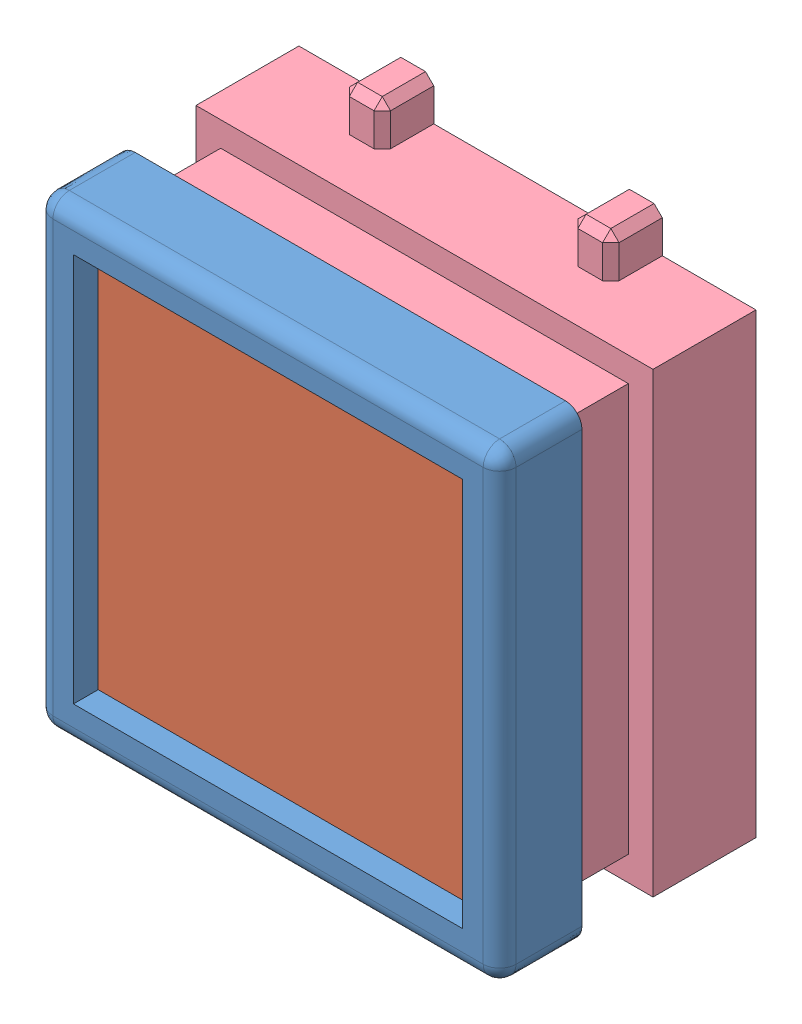
SolidWorks assembly RWR Control Indicator, configuration FAIL - BIT. Lengths in mm.
Overall size (14.29 16.64 9.53).
12 component instances, 8 part files, 8 mates.
Components (placement in the parent):
- .55 SQ Indicator Bezel-1: .55 SQ Indicator Bezel [Default] at origin size (14.29 14.29 2.54)
- .55 SQ Indicator Legend Cover-1: .55 SQ Indicator Legend Cover [BLANK] at (0 0 -0.762) x (-1 0 0) z (0 0 -1) size (12.57 12.57 0.76)
- .55 SQ Indicator Legend-1: .55 SQ Indicator Legend [FAIL - BIT] at (0 0 -1.524) x (-1 0 0) z (0 0 -1) size (12.57 12.57 0.13)
- .55 SQ Indicator Actuator-1: .55 SQ Indicator Actuator [Default] at (0 0 -1.651) x (-1 0 0) z (0 0 -1) size (14.1 16.64 6.35)
- .55 SQ Indicator Legend Diffuser-1: .55 SQ Indicator Legend Diffuser [Green] at (-23.4937 80.9593 -1.651) x (1 0 0) z (0 0 -1) size (11.3 5.28 0.13)
- 99461A505 - PHS, 0-42 X .125, SELF TAPPING, 18-8-1: 99461A505 - PHS, 0-42 X .125, SELF TAPPING, 18-8 [99461A505] at (12.7 -106.3625 -6.4135) x (1 0 0) z (0 0 -1) size (2.95 2.95 4.36)
- GX06400 - SWITCH, DOME, SNAPTRON, 6.3mm DIA, 400gf-1: GX06400 - SWITCH, DOME, SNAPTRON, 6.3mm DIA, 400gf [Default] at (12.7 -106.3625 -9.525) x (0.707107 -0.707107 0) z (-0.707107 -0.707107 0) size (6.3 0.36 6.3)
- IN-S63AT5UW - LED, 0603, WHITE, 3V, 5mA, 900mcd-3: IN-S63AT5UW - LED, 0603, WHITE, 3V, 5mA, 900mcd [Default] at (8.4832 -103.3462 -9.5186) x (0 -1 0) z (0 0 1) size (0.79 1.61 0.71)
- IN-S63AT5UW - LED, 0603, WHITE, 3V, 5mA, 900mcd-4: IN-S63AT5UW - LED, 0603, WHITE, 3V, 5mA, 900mcd [Default] at (16.9167 -103.3462 -9.5186) x (0 -1 0) z (0 0 1) size (0.79 1.61 0.71)
- IN-S63AT5UW - LED, 0603, WHITE, 3V, 5mA, 900mcd-5: IN-S63AT5UW - LED, 0603, WHITE, 3V, 5mA, 900mcd [Default] at (8.4832 -109.3787 -9.5186) x (0 -1 0) z (0 0 1) size (0.79 1.61 0.71)
- IN-S63AT5UW - LED, 0603, WHITE, 3V, 5mA, 900mcd-6: IN-S63AT5UW - LED, 0603, WHITE, 3V, 5mA, 900mcd [Default] at (16.9167 -109.3787 -9.5186) x (0 -1 0) z (0 0 1) size (0.79 1.61 0.71)
- .55 SQ Indicator Legend Diffuser-2: .55 SQ Indicator Legend Diffuser [Green] at (-23.4937 74.9268 -1.651) x (1 0 0) z (0 0 -1) size (11.3 5.28 0.13)
Mates (geometry in assembly coordinates):
- Coincident72: coincident: plane of .55 SQ Indicator Legend-1 through (0 0 -1.651) normal (0 0 -1); plane of .55 SQ Indicator Legend Diffuser-1 through (-23.4937 80.9593 -1.651) normal (0 0 1)
- Width7: width: plane of .55 SQ Indicator Legend Diffuser-1 through (18.3515 -105.9878 -1.778) normal (0 -1 0); plane of .55 SQ Indicator Actuator-1 through (7.0485 -100.7047 -1.778) normal (0 1 0); plane of .55 SQ Indicator Legend Diffuser-1 through (6.4135 -106.1085 -8.001) normal (0 1 0); plane of .55 SQ Indicator Actuator-1 through (6.4135 -100.584 -8.001) normal (0 -1 0)
- Width8: width: plane of .55 SQ Indicator Legend Diffuser-1 through (7.0485 -105.9878 -1.778) normal (-1 0 0); plane of .55 SQ Indicator Legend Diffuser-1 through (18.3515 -100.7047 -1.778) normal (1 0 0); plane of .55 SQ Indicator Actuator-1 through (6.9215 -112.649 -8.001) normal (1 0 0); plane of .55 SQ Indicator Actuator-1 through (18.4785 -100.076 -8.001) normal (-1 0 0)
- Concentric7: concentric: cylinder of .55 SQ Indicator Actuator-1 through (12.7 -106.3625 -8.001) axis (0 0 -1) radius 0.5956; cylinder of 99461A505 - PHS, 0-42 X .125, SELF TAPPING, 18-8-1 through (12.7 -106.3625 -8.9916) axis (0 0 1) radius 1.4732
- Coincident76: coincident: plane of .55 SQ Indicator Actuator-1 through (0 0 -8.001) normal (0 0 -1); plane of 99461A505 - PHS, 0-42 X .125, SELF TAPPING, 18-8-1 through (12.7 -106.3625 -8.001) normal (0 0 1)
- Coincident77: coincident: line of .55 SQ Indicator Legend Diffuser-1 through (7.0485 -105.9878 -1.778) axis (0 1 0); plane of .55 SQ Indicator Legend Diffuser-2 through (7.0485 -112.0204 -1.778) normal (-1 0 0)
- Width9: width anti-aligned: plane of .55 SQ Indicator Actuator-1 through (18.9865 -112.141 -8.001) normal (0 1 0); plane of .55 SQ Indicator Legend Diffuser-2 through (6.4135 -106.6165 -8.001) normal (0 -1 0); plane of .55 SQ Indicator Actuator-1 through (18.3515 -112.0204 -1.778) normal (0 -1 0); plane of .55 SQ Indicator Legend Diffuser-2 through (7.0485 -106.7371 -1.778) normal (0 1 0)
- Coincident78: coincident anti-aligned: plane of .55 SQ Indicator Legend-1 through (0 0 -1.651) normal (0 0 -1); plane of .55 SQ Indicator Legend Diffuser-2 through (-23.4937 74.9268 -1.651) normal (0 0 1)
